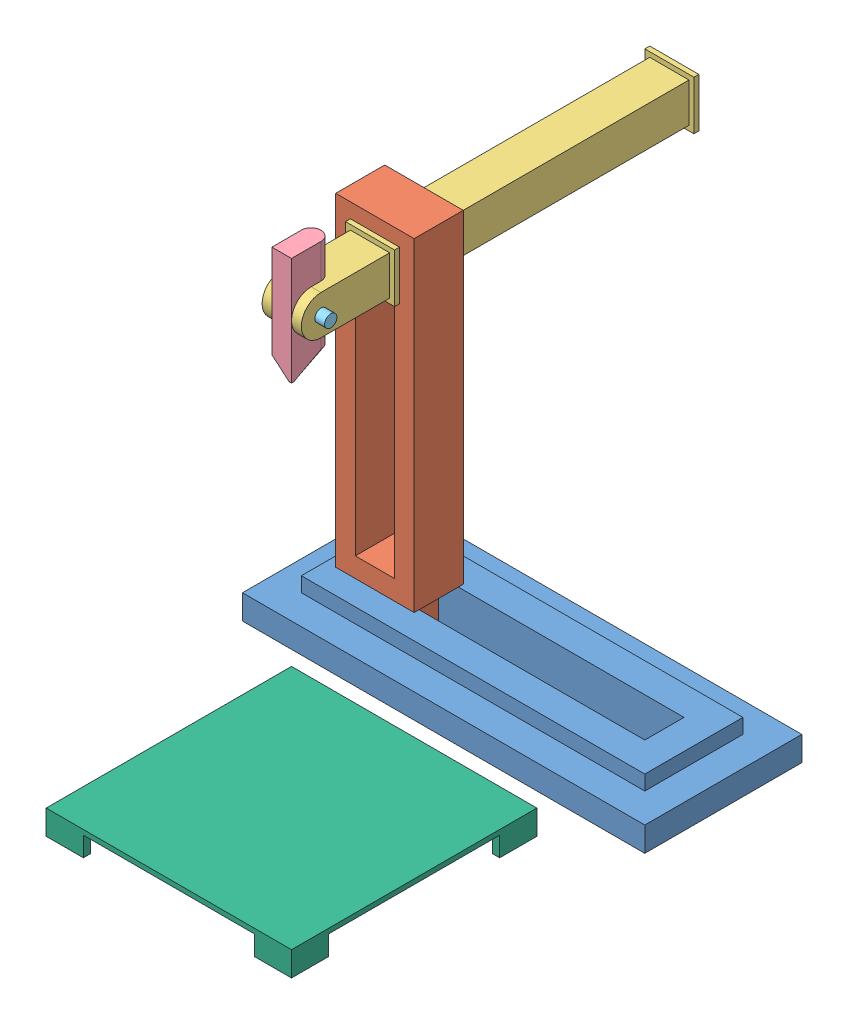
SolidWorks assembly Assem_3d_robot, configuration Default. Lengths in mm.
Overall size (820 770 1300).
6 component instances, 6 part files, 16 mates.
Components (placement in the parent):
- Bottom_part-3: Bottom_part [Default] at (410 40 160) x (1 0 0) z (0 0 -1) size (820 80 320)
- Middle_part-1: Middle_part [Default] at (160 410 160) x (0 1 0) z (1 0 0) size (740 100 160)
- Up_part-1: Up_part [Default] at (160 620 -70) x (0 0 -1) z (1 0 0) size (800 100 100)
- pen_part-1: pen_part [Default] at (160 720 340) x (-1 0 0) z (0 0 1) size (40.02 220.01 80.01)
- bolt_part-1: bolt_part [Default] at (110 660 360) size (110 35 35)
- floor_part-1: floor_part [Default] at (430 40 650) size (500 50 500)
Mates (geometry in assembly coordinates):
- Coincident1: coincident anti-aligned: plane of Bottom_part-3 through (410 50 200) normal (0 0 -1); plane of Middle_part-1 through (160 410 200) normal (0 0 1)
- Coincident2: coincident aligned: plane of Bottom_part-3 through (410 0 160) normal (0 -1 0); plane of Middle_part-1 through (160 0 120) normal (0 -1 0)
- Coincident3: coincident anti-aligned: plane of Middle_part-1 through (200 410 210) normal (-1 0 0); plane of Up_part-1 through (200 700 260) normal (1 0 0)
- Width2: width aligned: plane of Middle_part-1 through (160 700 210) normal (0 -1 0); plane of Up_part-1 through (160 120 210) normal (0 1 0); plane of Middle_part-1 through (160 620 -70) normal (0 -1 0); plane of Up_part-1 through (160 700 -70) normal (0 1 0)
- Width3: width anti-aligned: plane of Up_part-1 through (160 620 210) normal (0 0 -1); plane of Middle_part-1 through (160 620 -390) normal (0 0 1); plane of Up_part-1 through (160 410 210) normal (0 0 1); plane of Middle_part-1 through (160 410 110) normal (0 0 -1)
- Width4: width anti-aligned: plane of Bottom_part-3 through (700 50 160) normal (-1 0 0); plane of Middle_part-1 through (120 50 160) normal (1 0 0); plane of Bottom_part-3 through (200 410 120) normal (1 0 0); plane of Middle_part-1 through (120 410 120) normal (-1 0 0)
- Concentric2: concentric aligned: cylinder of Up_part-1 through (160 530.5573 340) axis (0 1 0) radius 20; cylinder of pen_part-1 through (160 770 340) axis (0 1 0) radius 20
- Concentric3: concentric aligned: cylinder of Up_part-1 through (6.8629 660 360) axis (1 0 0) radius 12.5; cylinder of pen_part-1 through (104.6447 660 360) axis (1 0 0) radius 12.5
- Concentric4: concentric aligned: cylinder of Up_part-1 through (6.8629 660 360) axis (1 0 0) radius 12.5; cylinder of bolt_part-1 through (220 660 360) axis (1 0 0) radius 12.5
- Coincident4: coincident anti-aligned: plane of Up_part-1 through (120 700 260) normal (-1 0 0); plane of bolt_part-1 through (120 660 347.5) normal (1 0 0)
- Parallel1: parallel aligned: plane of Bottom_part-3 through (410 0 160) normal (0 -1 0); plane of floor_part-1 through (430 0 650) normal (0 -1 0)
- Parallel2: parallel aligned: plane of Bottom_part-3 through (410 0 160) normal (0 -1 0); plane of floor_part-1 through (430 0 650) normal (0 -1 0)
- Coincident10: coincident anti-aligned: plane of Bottom_part-3 through (410 0 160) normal (0 -1 0)
- Coincident11: coincident anti-aligned: plane of floor_part-1 through (430 0 650) normal (0 -1 0)
- Coincident15: coincident: point of assembly; point of Bottom_part-3
- Symmetric1: symmetric anti-aligned: plane of Bottom_part-3 through (0 50 160) normal (-1 0 0); plane of floor_part-1 through (430 50 650) normal (0 1 0)
